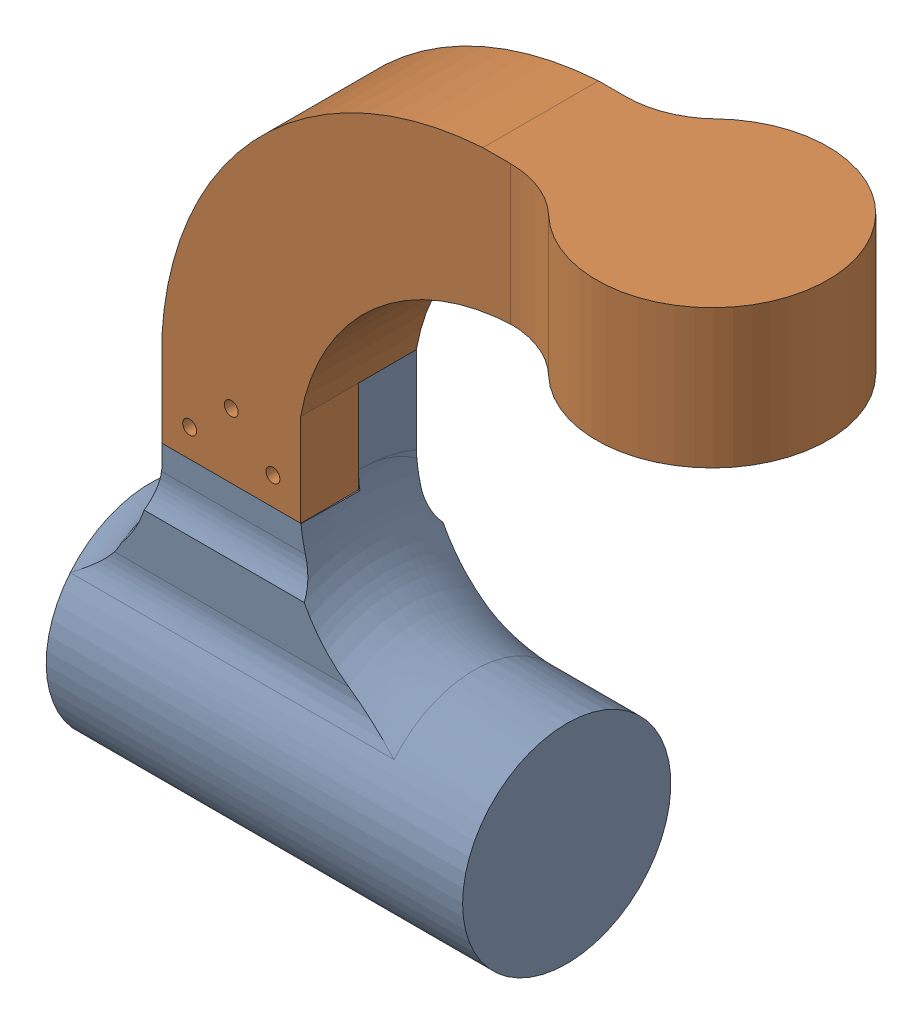
SolidWorks assembly MirrorWheel_Steer_Assembly1, configuration Default. Lengths in mm.
Overall size (146.44 156.21 50).
2 component instances, 2 part files, 6 mates.
Components (placement in the parent):
- MirrorMotor_holder_end_wheels-1: MirrorMotor_holder_end_wheels [Default] at (-15 -43.7083 -12.5) x (0 1 0) z (-1 0 0) size (86.21 45 90)
- MirrorSteer_to_motor_holder-1: MirrorSteer_to_motor_holder [Default] at origin size (131.44 90 50)
Mates (geometry in assembly coordinates):
- Coincident1: coincident aligned: plane of MirrorSteer_to_motor_holder-1 through (0 0 0) normal (0 0 1)
- Coincident2: coincident aligned: plane of MirrorSteer_to_motor_holder-1 through (0 0 0) normal (0 1 0)
- Coincident3: coincident aligned: plane of MirrorSteer_to_motor_holder-1 through (0 0 0) normal (1 0 0)
- Coincident4: coincident anti-aligned: plane of MirrorMotor_holder_end_wheels-1 through (48 20 -12.5) normal (0 0 1); plane of MirrorSteer_to_motor_holder-1 through (49 0 -12.5) normal (0 0 -1)
- Coincident5: coincident anti-aligned: plane of MirrorMotor_holder_end_wheels-1 through (48 20 -25) normal (0 1 0); plane of MirrorSteer_to_motor_holder-1 through (49 20 -12.5) normal (0 -1 0)
- Coincident6: coincident aligned: plane of MirrorMotor_holder_end_wheels-1 through (30 -10 0) normal (1 0 0); plane of MirrorSteer_to_motor_holder-1 through (30 0 -25) normal (1 0 0)
